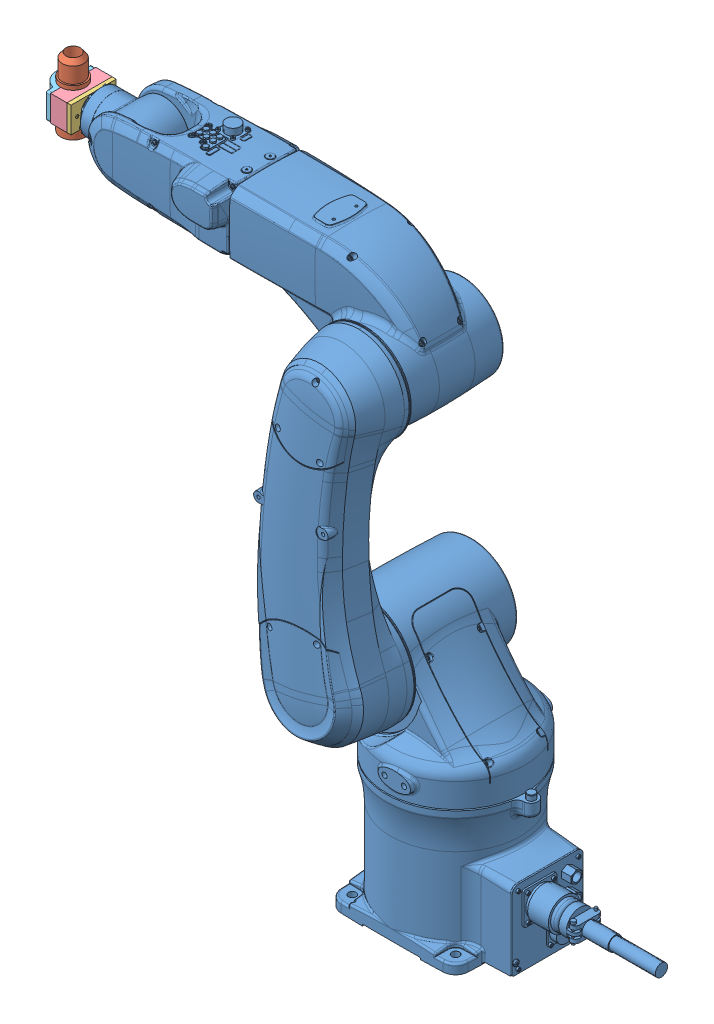
SolidWorks assembly end_effectorplusdenso_1, configuration Default. Lengths in mm.
Overall size (949.45 852.66 290.42).
16 component instances, 8 part files, 5 mates.
Components (placement in the parent):
- VS-6577-B_asm-1: VS-6577-B_asm [Default] at (160.2417 -407.7882 -66.1988) size (892.3 852.66 290.42)
- NozzleClampAssembly-1: NozzleClampAssembly [Default] at (-399.7583 382.2728 -66.1988) x (-1 0 0) z (0 0 -1) size (57.15 107.2 69.85)
  - Nozzle_C-1: Nozzle_C [Default] at (31.75 -49.911 0) x (0.951012 0 -0.309152) z (0.309152 0 0.951012) size (38.1 107.2 38.1)
  - attachment disk_C-1: attachment disk_C [Default] at (6.35 0 0) x (0 0 -1) z (0 1 0) size (69.85 6.63 39.88)
  - Clamp_B-1: Clamp_B [Default] at (31.75 19.939 0) x (0 0 1) z (-1 0 0) size (69.85 39.88 25.4)
  - Clamp_A-1: Clamp_A [Default] at (31.75 19.939 0) x (0 0 1) z (-1 0 0) size (69.85 39.88 25.4)
  - 91266A258_Thread-Locking Hex Drive Flat Head Screws-1: 91266A258_Thread-Locking Hex Drive Flat Head Screws [91266A258] at (31.75 0 25.4) x (0 -0.258689 -0.965961) z (1 0 0) (suppressed, hidden)
  - 91266A254_Thread-Locking Hex Drive Flat Head Screws-1: 91266A254_Thread-Locking Hex Drive Flat Head Screws [91266A254] at (6.35 11.1369 11.1369) x (0 0 -1) z (1 0 0) (suppressed, hidden)
  - 91266A258_Thread-Locking Hex Drive Flat Head Screws-2: 91266A258_Thread-Locking Hex Drive Flat Head Screws [91266A258] at (31.75 0 -25.4) x (0 -0.258689 0.965961) z (1 0 0) (suppressed, hidden)
  - 91251A345_Black-Oxide Alloy Steel Socket Head Screw-1: 91251A345_Black-Oxide Alloy Steel Socket Head Screw [91251A345] at (30.988 -12.7 30.1625) x (0 0 -1) z (1 0 0) (suppressed, hidden)
  - 91251A345_Black-Oxide Alloy Steel Socket Head Screw-2: 91251A345_Black-Oxide Alloy Steel Socket Head Screw [91251A345] at (30.988 12.7 30.1625) x (0 0 1) z (1 0 0) (suppressed, hidden)
  - 91251A345_Black-Oxide Alloy Steel Socket Head Screw-3: 91251A345_Black-Oxide Alloy Steel Socket Head Screw [91251A345] at (30.988 -12.7 -30.1625) x (0 0 -1) z (1 0 0) (suppressed, hidden)
  - 91251A345_Black-Oxide Alloy Steel Socket Head Screw-4: 91251A345_Black-Oxide Alloy Steel Socket Head Screw [91251A345] at (30.988 12.7 -30.1625) x (0 0 1) z (1 0 0) (suppressed, hidden)
  - 91266A254_Thread-Locking Hex Drive Flat Head Screws-9: 91266A254_Thread-Locking Hex Drive Flat Head Screws [91266A254] at (6.35 -11.1369 11.1369) x (0 0 -1) z (1 0 0) (suppressed, hidden)
  - 91266A254_Thread-Locking Hex Drive Flat Head Screws-10: 91266A254_Thread-Locking Hex Drive Flat Head Screws [91266A254] at (6.35 11.1369 -11.1369) x (0 0 1) z (1 0 0) (suppressed, hidden)
  - 91266A254_Thread-Locking Hex Drive Flat Head Screws-11: 91266A254_Thread-Locking Hex Drive Flat Head Screws [91266A254] at (6.35 -11.1369 -11.1369) x (0 0 1) z (1 0 0) (suppressed, hidden)
Mates (geometry in assembly coordinates):
- Coincident25: coincident anti-aligned: plane of VS-6577-B_asm-1 through (-399.7583 401.7618 -85.7622) normal (-1 0 0); plane of Assem3^end_effectorplusdenso_1-1/attachment disk_C-1 through (-399.7583 382.2728 -66.1988) normal (1 0 0)
- Tangent8: tangent aligned: cylinder of VS-6577-B_asm-1 through (-393.7083 382.2118 -66.1988) axis (-1 0 0) radius 20; plane of Assem3^end_effectorplusdenso_1-1/attachment disk_C-1 through (-399.7583 402.2118 -31.2738) normal (0 1 0)
- Width5: width: plane of Assem3^end_effectorplusdenso_1-1/Clamp_B-1 through (-431.5083 362.3338 -31.2738) normal (0 0 1); plane of VS-6577-B_asm-1 through (-406.1083 362.3338 -101.1238) normal (0 0 -1); cylinder of Assem3^end_effectorplusdenso_1-1/Clamp_B-1 through (-393.7083 382.2118 -66.1988) axis (-1 0 0) radius 20
- Tangent9: tangent aligned: cylinder of VS-6577-B_asm-1 through (-393.7083 382.2118 -66.1988) axis (-1 0 0) radius 20; plane of Assem3^end_effectorplusdenso_1-1/Clamp_B-1 through (-431.5083 402.2118 -66.1988) normal (0 1 0)
- Parallel5: parallel anti-aligned: plane of VS-6577-B_asm-1 through (73.587 -402.7882 20.4559) normal (0 -1 0); plane of Assem3^end_effectorplusdenso_1-1/Clamp_B-1 through (-431.5083 402.2118 -66.1988) normal (0 1 0)
